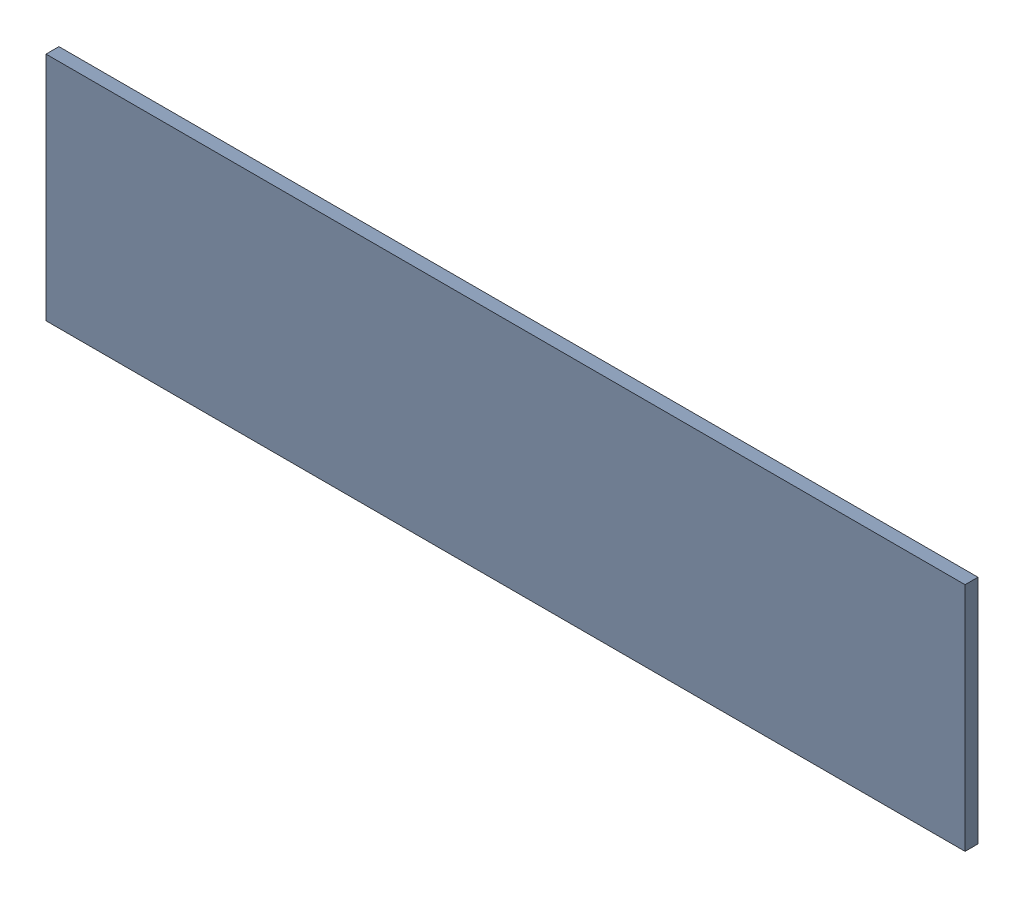
SolidWorks assembly PS+, configuration Default. Lengths in mm.
Overall size (1.8 0.45 0.03).
4 component instances, 1 part files, 0 mates.
Components (placement in the parent):
- 6701982208-1:  [Default] at (27.7 14.8 0) (suppressed, hidden)
- 6327396352-1: 6327396352 [Default] at (-3.4196 0.6333 0) size (1.8 0.45 0.03)
  - 6701982208-1:  [Default] at (27.7 14.8 0) (suppressed, hidden)
  - Extruded-24-1: Extruded-24 [Default] at origin size (1.8 0.45 0.03)
